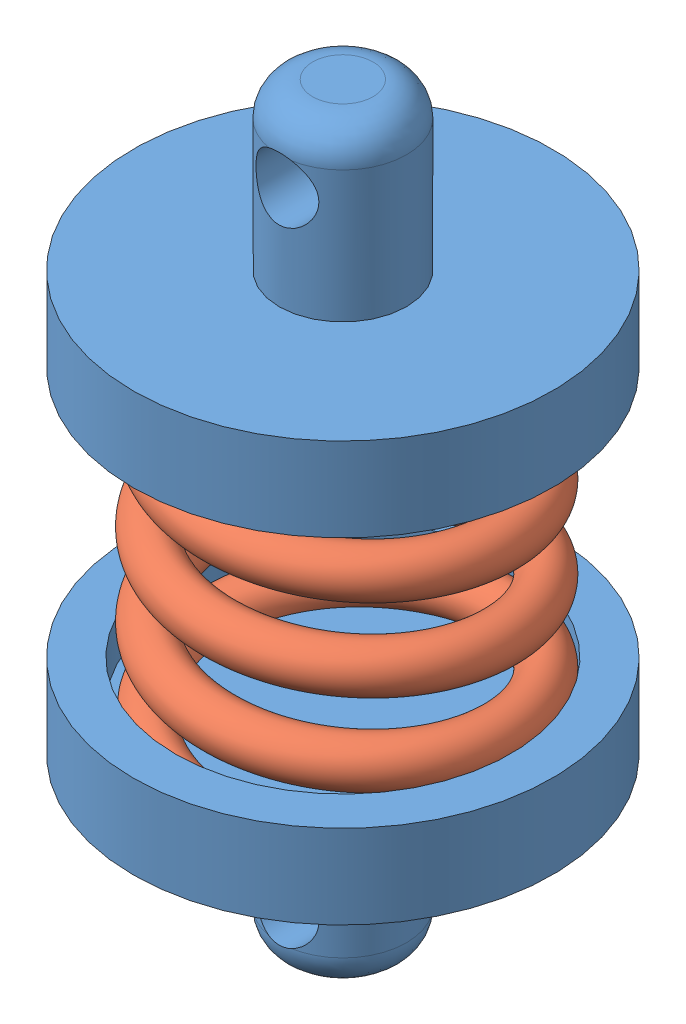
SolidWorks assembly Spring guide assembly, configuration Default. Lengths in mm.
Overall size (31.75 56.77 31.75).
3 component instances, 2 part files, 3 mates.
Components (placement in the parent):
- SPRING GUIDE-1: SPRING GUIDE [Default] at (-18.26 5.2904 -26.1179) size (31.75 18.86 31.75)
- SPRING GUIDE-2: SPRING GUIDE [Default] at (-18.26 -51.4786 -26.1179) x (-1 0 0) z (0 0 1) size (31.75 18.86 31.75)
- Heel Spring-1: Heel Spring [9657K513] at (-18.0668 -48.4941 -26.2147) x (1 0 0) z (0 -1 0) size (26.33 25.44 26.85)
Mates (geometry in assembly coordinates):
- Coincident2: coincident: axis of SPRING GUIDE-1 through (-18.26 -0.0636 -26.1179) axis (0 1 0); axis of SPRING GUIDE-2 through (-18.26 -46.1246 -26.1179) axis (0 -1 0)
- Coincident4: coincident anti-aligned: plane of SPRING GUIDE-2 through (-30.96 -35.7941 -26.1179) normal (0 1 0); plane of Heel Spring-1 through (-18.0668 -35.7941 -26.2147) normal (0 -1 0)
- Parallel1: parallel aligned: line of SPRING GUIDE-1 through (-18.26 0.5279 -30.8675) axis (0 0 1); line of SPRING GUIDE-2 through (-18.26 -46.7161 -30.8675) axis (0 0 1)
